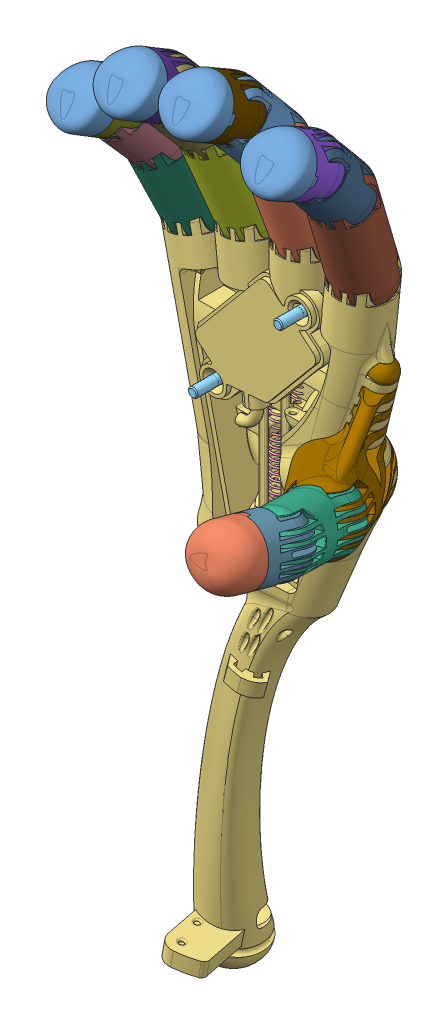
SolidWorks assembly a-hand-rechts-komplett-v01, configuration links01. Lengths in mm.
Overall size (110.58 275.87 105.41).
27 component instances, 21 part files, 10 mates.
Components (placement in the parent):
- p-fingerkuppe-12.4-1: p-fingerkuppe-12.4 [linksStandard] at (0 124.4732 39.4578) x (-1 0 0) z (0 0.866025 -0.5) size (17.55 9.03 17.93)
- p-fingerkuppe-12.4-2: p-fingerkuppe-12.4 [linksStandard] at (-23.2567 117.6716 37.2523) x (-0.994522 -0.104528 0) z (-0.090524 0.861281 -0.5) size (17.55 9.03 17.93)
- p-fingerkuppe-12.4-3: p-fingerkuppe-12.4 [linksStandard] at (-44.0904 100.646 31.7772) x (-0.976296 -0.21644 0) z (-0.187442 0.845497 -0.5) size (17.55 9.03 17.93)
- p-fingerkuppe-12.4-4: p-fingerkuppe-12.4 [linksStandard] at (23.3039 118.1213 36.2845) x (-0.994522 0.104528 0) z (0.090524 0.861281 -0.5) size (17.55 9.03 17.93)
- p-fingerkuppe-18-1: p-fingerkuppe-18 [linksStandard] at (38.286 33.1248 70.5385) x (-0.220756 0.946374 -0.235889) z (0.973336 0.229218 0.008717) size (18.01 12.53 19.06)
- z-sensor-v01-1: z-sensor-v01 [linksStandard] at (-7.7515 38.0869 5.525) x (0.642788 0.766044 0) z (0 0 1) size (52.4 25.94 6.1)
- z-zugfeder-40055-1: z-zugfeder-40055 [linksStandard] at (-6 -15 -4) x (-1 0 0) z (0 0 -1) size (5.53 54.95 5.5)
- z-zugfeder-40055-2: z-zugfeder-40055 [linksStandard] at (-13 -13.5 -4) x (-1 0 0) z (0 0 -1) size (5.53 54.95 5.5)
- n-se_schr_in_6kt_din_7991_m03x10-1: n-se_schr_in_6kt_din_7991_m03x10 [linksStandard] at (5.7471 54.1739 6.825) x (0.766044 -0.642788 0) z (0 0 1) size (6 6 10.1)
- n-se_schr_in_6kt_din_7991_m03x10-2: n-se_schr_in_6kt_din_7991_m03x10 [linksStandard] at (-21.25 22 6.825) x (0.766044 -0.642788 0) z (0 0 1) size (6 6 10.1)
- a-hand-rechts-step-v01-oa0-1: a-hand-rechts-step-v01-oa0 [linksStandard] at origin size (110.58 275.87 102.92)
  - p-daumen-seg-2-step-v01-1: p-daumen-seg-2-step-v01 [linksStandard] at (33.2419 21.3452 28) x (0.220756 -0.946374 0.235889) z (-0.935951 -0.137525 0.324164) size (20.69 43.22 21.88)
  - p-ringfinger-seg-1-step-v02-1: p-ringfinger-seg-1-step-v02 [linksStandard] at (-12.7428 17.6388 -17.8902) x (0.994522 0.104528 0) z (0.035751 -0.340147 0.939693) size (19.08 47.31 19.03)
  - p-zeigfinger-seg-3-step-v02-1: p-zeigfinger-seg-3-step-v02 [linksStandard] at (15.5674 44.5129 -91.9113) x (0.994522 -0.104528 0) z (-0.090524 -0.861281 0.5) size (19.01 23.27 19)
  - p-daumen-seg-1-step-v01-1: p-daumen-seg-1-step-v01 [linksStandard] at (11.6667 9.3333 0) x (0.090387 -0.785385 0.612372) z (-0.813798 0.296198 0.5) size (51 61.46 25.3)
  - p-zeigfinger-seg-2-step-v02-1: p-zeigfinger-seg-2-step-v02 [linksStandard] at (8.7304 -20.5367 -87.9966) x (0.994522 -0.104528 0) z (-0.06719 -0.639266 0.766044) size (19.2 35.59 19.73)
  - p-zeigfinger-seg-1-step-v02-1: p-zeigfinger-seg-1-step-v02 [linksStandard] at (12.8427 18.5894 -17.8254) x (0.994522 -0.104528 0) z (-0.035751 -0.340147 0.939693) size (19.08 48.86 19.03)
  - p-ringfinger-seg-2-step-v02-1: p-ringfinger-seg-2-step-v02 [linksStandard] at (-8.5153 -22.5832 -88.3762) x (0.994522 0.104528 0) z (0.06719 -0.639266 0.766044) size (19.2 37.93 19.73)
  - p-kleinerfinger-seg-2-step-v02-1: p-kleinerfinger-seg-2-step-v02 [linksStandard] at (-20.1072 -7.5356 -67.7998) x (0.976296 0.21644 0) z (0.139125 -0.627551 0.766044) size (19.09 34.83 19.68)
  - p-daumen-seg-3-v01-1: p-daumen-seg-3-v01 [linksStandard] at (39.6432 28.1665 49.3761) x (-0.062319 0.227675 0.971741) z (-0.973336 -0.229218 -0.008717) size (28.23 20.09 20.4)
  - p-kleinerfinger-seg-1-step-v02-1: p-kleinerfinger-seg-1-step-v02 [linksStandard] at (-23.9615 9.8501 -18.4087) x (0.976296 0.21644 0) z (0.074027 -0.333913 0.939693) size (19.08 41.2 19.03)
  - p-kleinerfinger-seg-3-step-v02-1: p-kleinerfinger-seg-3-step-v02 [linksStandard] at (-27.0329 23.7045 -104.725) x (0.976296 0.21644 0) z (0.187442 -0.845497 0.5) size (18.67 21.72 17.82)
  - p-ringfinger-seg-3-step-v02-1: p-ringfinger-seg-3-step-v02 [linksStandard] at (-15.4056 42.9733 -92.8418) x (0.994522 0.104528 0) z (0.090524 -0.861281 0.5) size (19.01 23.27 19)
  - p-mittelfinger-seg-3-step-v02-1: p-mittelfinger-seg-3-step-v02 [linksStandard] at (0 68.8301 -56.9189) x (1 0 0) z (0 -0.866025 0.5) size (19.01 24.05 19)
  - p-mittelfinger-seg-2-step-v02-1: p-mittelfinger-seg-2-step-v02 [linksStandard] at (0 52.3745 -28.6799) x (1 0 0) z (0 -0.642788 0.766044) size (19.2 39.53 19.78)
  - p-mittelfinger-seg-1-step-v02-1: p-mittelfinger-seg-1-step-v02 [linksStandard] at (0 -15.4293 -31.0937) x (1 0 0) z (0 -0.34202 0.939693) size (19.08 48.86 19.03)
  - p-handfläche-teil-2-v01-1: p-handfläche-teil-2-v01 [linksStandard] at origin size (71.41 221.99 39.87)
Mates (geometry in assembly coordinates):
- Konzentrisch1: concentric aligned: cylinder of p-fingerkuppe-18-1 through (42.0252 19.4643 12.234) axis (-0.062319 0.227675 0.971741) radius 2.5; cylinder of a-hand-rechts-step-v01-oa0-1/p-daumen-seg-3-v01-1 through (43.3824 14.506 -8.9283) axis (-0.062319 0.227675 0.971741) radius 2.5
- Konzentrisch2: concentric anti-aligned: cylinder of p-fingerkuppe-18-1 through (41.94 22.6684 60.7708) axis (0.38642 -0.892193 0.233819) radius 0.4; cylinder of a-hand-rechts-step-v01-oa0-1/p-daumen-seg-3-v01-1 through (41.5701 23.5224 60.547) axis (-0.38642 0.892193 -0.233819) radius 0.4
- Konzentrisch3: concentric anti-aligned: cylinder of p-fingerkuppe-12.4-4 through (20.1681 88.2856 -15.6771) axis (0.052264 0.497261 0.866025) radius 2; cylinder of a-hand-rechts-step-v01-oa0-1/p-zeigfinger-seg-3-step-v02-1 through (12.4315 14.6772 -143.8728) axis (-0.052264 -0.497261 -0.866025) radius 2
- Konzentrisch4: concentric aligned: cylinder of p-fingerkuppe-12.4-4 through (30.8364 113.8706 28.3401) axis (0.995132 0.046619 -0.086824) radius 0.4; cylinder of a-hand-rechts-step-v01-oa0-1/p-zeigfinger-seg-3-step-v02-1 through (29.8538 113.8246 28.4258) axis (0.995132 0.046619 -0.086824) radius 0.4
- Konzentrisch5: concentric anti-aligned: cylinder of p-fingerkuppe-12.4-1 through (0 94.4732 -12.5038) axis (0 0.5 0.866025) radius 2; cylinder of a-hand-rechts-step-v01-oa0-1/p-mittelfinger-seg-3-step-v02-1 through (0 38.8301 -108.8804) axis (0 -0.5 -0.866025) radius 2
- Konzentrisch6: concentric aligned: cylinder of p-fingerkuppe-12.4-1 through (6.9631 119.4616 32.4208) axis (-0.984808 0.150384 -0.086824) radius 0.4; cylinder of a-hand-rechts-step-v01-oa0-1/p-mittelfinger-seg-3-step-v02-1 through (6.9631 119.4616 32.4208) axis (-0.984808 0.150384 -0.086824) radius 0.4
- Konzentrisch7: concentric anti-aligned: cylinder of p-fingerkuppe-12.4-2 through (-20.1208 87.836 -14.7093) axis (-0.052264 0.497261 0.866025) radius 2; cylinder of a-hand-rechts-step-v01-oa0-1/p-ringfinger-seg-3-step-v02-1 through (-12.2697 13.1376 -144.8033) axis (0.052264 -0.497261 -0.866025) radius 2
- Konzentrisch8: concentric aligned: cylinder of p-fingerkuppe-12.4-2 through (-15.0051 115.08 29.3079) axis (0.963693 0.2525 -0.086824) radius 0.4; cylinder of a-hand-rechts-step-v01-oa0-1/p-ringfinger-seg-3-step-v02-1 through (-15.9566 114.8307 29.3936) axis (0.963693 0.2525 -0.086824) radius 0.4
- Konzentrisch9: concentric anti-aligned: cylinder of p-fingerkuppe-12.4-3 through (-37.5973 71.3571 -20.1843) axis (-0.10822 0.488148 0.866025) radius 2; cylinder of a-hand-rechts-step-v01-oa0-1/p-kleinerfinger-seg-3-step-v02-1 through (-20.5397 -5.5844 -156.6865) axis (0.10822 -0.488148 -0.866025) radius 2
- Konzentrisch10: concentric aligned: cylinder of p-fingerkuppe-12.4-3 through (-49.6922 95.6635 23.9552) axis (0.994013 0.066332 0.086824) radius 0.4; cylinder of a-hand-rechts-step-v01-oa0-1/p-kleinerfinger-seg-3-step-v02-1 through (-51.6028 95.536 23.7883) axis (0.994013 0.066332 0.086824) radius 0.4
